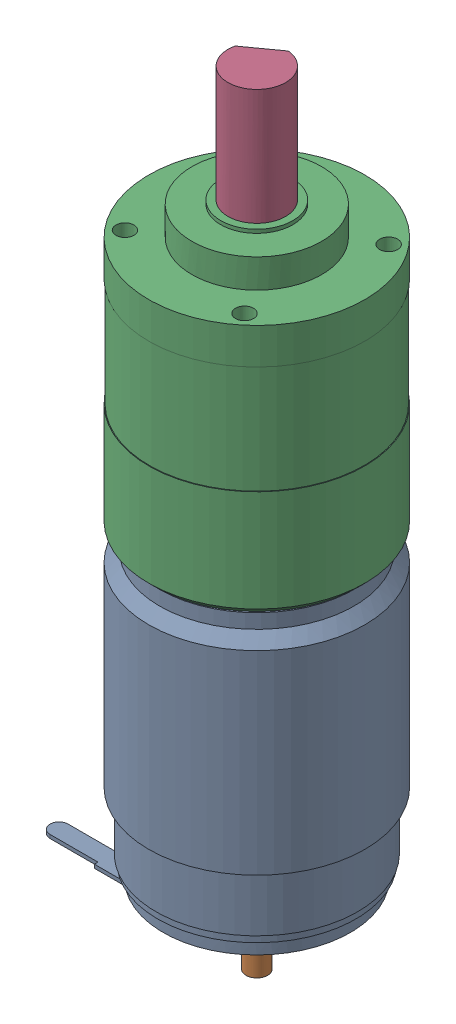
SolidWorks assembly Motoreducteur_Faulhauber_3042W024_30_1, configuration Default. Lengths in mm.
Overall size (42.24 108.6 42.24).
4 component instances, 4 part files, 8 mates.
Components (placement in the parent):
- corps_moteur_faulhauber_3042W024C-1: corps_moteur_faulhauber_3042W024C [Default] at (-5.2131 -12.6529 -1.1935) size (35.9 47.3 30)
- arbre_moteur_faulhauber_3042W024C-1: arbre_moteur_faulhauber_3042W024C [Default] at (-5.2131 41.7471 -1.1935) x (0 -1 0) z (-0.776717 0 -0.629849) size (65.3 4 4)
- corps_reducteur_faulhaber_30_1-1: corps_reducteur_faulhaber_30_1 [Default] at (-5.2131 64.4471 -1.1935) x (0.769654 0 -0.638462) z (0 -1 0) size (30 30 39.6)
- arbre_reducteur_faulhauber_30_1-1: arbre_reducteur_faulhauber_30_1 [Default] at (-5.2131 64.4471 -1.1935) x (0.811588 0 -0.584231) z (0.584231 0 0.811588) size (8 20.6 8)
Mates (geometry in assembly coordinates):
- Coaxiale1: concentric aligned: cylinder of corps_moteur_faulhauber_3042W024C-1 through (-5.2131 21.7471 -1.1935) axis (0 1 0) radius 2; cylinder of arbre_moteur_faulhauber_3042W024C-1 through (-5.2131 21.7471 -1.1935) axis (0 1 0) radius 2
- Coïncidente1: coincident anti-aligned: plane of corps_moteur_faulhauber_3042W024C-1 through (-5.2131 21.7471 -1.1935) normal (0 1 0); plane of arbre_moteur_faulhauber_3042W024C-1 through (-5.2131 21.7471 -1.1935) normal (0 -1 0)
- Coaxiale3: concentric aligned: cylinder of corps_moteur_faulhauber_3042W024C-1 through (-5.2131 30.8471 -1.1935) axis (0 -1 0) radius 5; cylinder of corps_reducteur_faulhaber_30_1-1 through (-5.2131 44.3471 -1.1935) axis (0 -1 0) radius 5
- Coïncidente2: coincident anti-aligned: plane of corps_moteur_faulhauber_3042W024C-1 through (-5.2131 29.3471 -1.1935) normal (0 1 0); plane of corps_reducteur_faulhaber_30_1-1 through (-5.2131 29.3471 -1.1935) normal (0 -1 0)
- Tangent1: tangent aligned: plane of corps_moteur_faulhauber_3042W024C-1 through (-18.2131 -13.1529 8.3565) normal (0 0 1); cylinder of corps_reducteur_faulhaber_30_1-1 through (-15.2186 64.4471 7.1065) axis (0 1 0) radius 1.25
- Coaxiale4: concentric aligned: cylinder of corps_reducteur_faulhaber_30_1-1 through (-5.2131 68.9481 -1.1935) axis (0 -1 0) radius 4; cylinder of arbre_reducteur_faulhauber_30_1-1 through (-5.2131 85.0471 -1.1935) axis (0 -1 0) radius 4
- Coïncidente3: coincident anti-aligned: plane of corps_reducteur_faulhaber_30_1-1 through (-5.2131 64.4471 -1.1935) normal (0 1 0); plane of arbre_reducteur_faulhauber_30_1-1 through (-5.2131 64.4471 -1.1935) normal (0 -1 0)
- Contr.Engrenages1: gear = 0.001 : 0.024: cylinder of arbre_reducteur_faulhauber_30_1-1 through (-5.2131 85.0471 -1.1935) axis (0 -1 0) radius 4; cylinder of arbre_moteur_faulhauber_3042W024C-1 through (-5.2131 -23.5529 -1.1935) axis (0 1 0) radius 1.5
